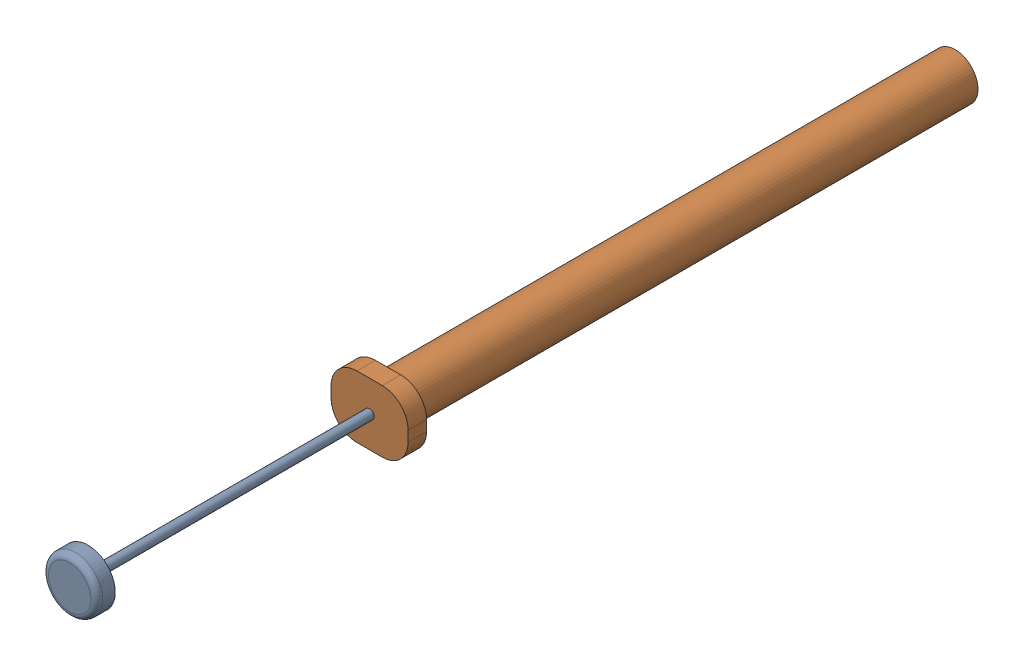
SolidWorks assembly SyringeAsm, configuration Default. Lengths in mm.
Overall size (13.25 11.35 152.29).
2 component instances, 2 part files, 4 mates.
Components (placement in the parent):
- Plunger-1: Plunger [Default] at (6.6231 -5.334 51.5829) x (0.246497 0.969144 0) z (-0.969144 0.246497 0) size (9.33 93.66 9.33)
- syringe-1: syringe [Default] x (1 0 0) z (0 0 -1) size (13.25 10.67 100.71)
Mates (geometry in assembly coordinates):
- Concentric1: concentric aligned: cylinder of Plunger-1 through (6.6231 -5.334 -42.0796) axis (0 0 1) radius 0.7937; cylinder of syringe-1 through (6.6231 -5.334 -100.711) axis (0 0 1) radius 0.7937
- Coincident1: coincident anti-aligned: plane of syringe-1 through (0 0 0) normal (0 0 -1)
- Coincident2: coincident anti-aligned: plane of syringe-1 through (0 0 0) normal (0 -1 0)
- Coincident3: coincident aligned: plane of syringe-1 through (0 0 0) normal (1 0 0)
